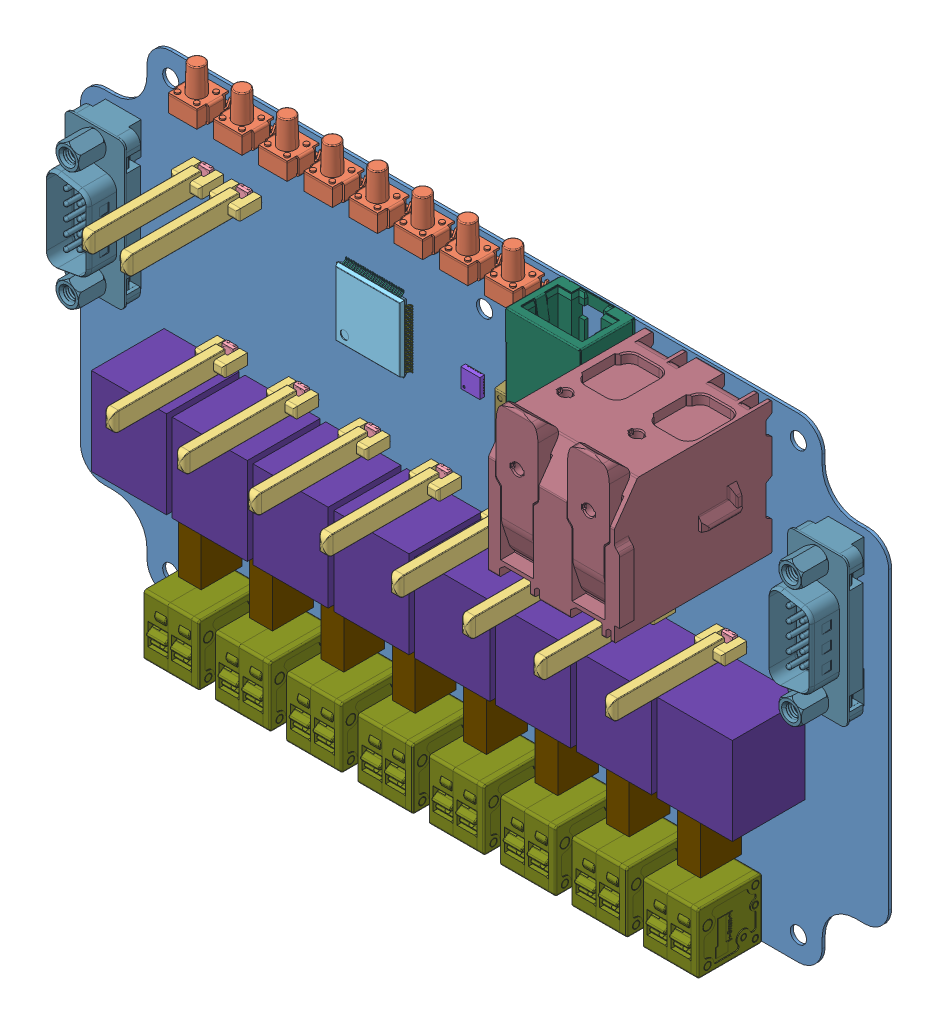
SolidWorks assembly KR-Df-01-EL-00 PCBA 2024_01_12, configuration Default. Lengths in mm.
Overall size (170 105.11 36.71).
192 component instances, 18 part files, 0 mates.
Components (placement in the parent):
- KR-Df-01-EL-00 PCBA 2024_01_12.step-1: KR-Df-01-EL-00 PCBA 2024_01_12.step [Default] at origin size (170 105.11 36.71)
  - Board.step-1: Board.step [Default] at origin size (170 100 0.62)
    - Open CASCADE STEP translator 7.5 2.1.1.step-1: Open CASCADE STEP translator 7.5 2.1.1.step [Default] at (0 0 -0.6237) size (170 100 0.62)
  - S607.step-1: S607.step [Default] at origin size (8.41 12.37 10.52)
    - 1-1825027-1.step-1: 1-1825027-1.step [Default] at (95 95.3 0) x (-1 0 0) z (0 1 0) size (8.41 10.52 12.37)
  - S606.step-1: S606.step [Default] at origin size (8.41 12.37 10.52)
    - 1-1825027-1.step-1: 1-1825027-1.step [Default] at (85.5 95.3 0) x (-1 0 0) z (0 1 0) size (8.41 10.52 12.37)
  - S605.step-1: S605.step [Default] at origin size (8.41 12.37 10.52)
    - 1-1825027-1.step-1: 1-1825027-1.step [Default] at (76 95.3 0) x (-1 0 0) z (0 1 0) size (8.41 10.52 12.37)
  - S604.step-1: S604.step [Default] at origin size (8.41 12.37 10.52)
    - 1-1825027-1.step-1: 1-1825027-1.step [Default] at (66.5 95.3 0) x (-1 0 0) z (0 1 0) size (8.41 10.52 12.37)
  - S603.step-1: S603.step [Default] at origin size (8.41 12.37 10.52)
    - 1-1825027-1.step-1: 1-1825027-1.step [Default] at (57 95.3 0) x (-1 0 0) z (0 1 0) size (8.41 10.52 12.37)
  - S602.step-1: S602.step [Default] at origin size (8.41 12.37 10.52)
    - 1-1825027-1.step-1: 1-1825027-1.step [Default] at (47.5 95.3 0) x (-1 0 0) z (0 1 0) size (8.41 10.52 12.37)
  - S601.step-1: S601.step [Default] at origin size (8.41 12.37 10.52)
    - 1-1825027-1.step-1: 1-1825027-1.step [Default] at (38 95.3 0) x (-1 0 0) z (0 1 0) size (8.41 10.52 12.37)
  - S600.step-1: S600.step [Default] at origin size (8.41 12.37 10.52)
    - 1-1825027-1.step-1: 1-1825027-1.step [Default] at (28.5 95.3 0) x (-1 0 0) z (0 1 0) size (8.41 10.52 12.37)
  - ME609.step-1: ME609.step [Default] at origin size (6.36 3.96 28.65)
    - BIVAR__INC_VLPR-24-1028-2_RGB8421504.step-1: BIVAR__INC_VLPR-24-1028-2_RGB8421504.step [Default] at (27 82 19.1) x (0 1 0) z (1 0 0) size (3.96 28.65 6.35)
  - ME608.step-1: ME608.step [Default] at origin size (6.36 3.96 28.65)
    - BIVAR__INC_VLPR-24-1028-2_RGB8421504.step-1: BIVAR__INC_VLPR-24-1028-2_RGB8421504.step [Default] at (35 82 19.1) x (0 1 0) z (1 0 0) size (3.96 28.65 6.35)
  - ME607.step-1: ME607.step [Default] at origin size (6.36 3.96 28.65)
    - BIVAR__INC_VLPR-24-1028-2_RGB8421504.step-1: BIVAR__INC_VLPR-24-1028-2_RGB8421504.step [Default] at (137 52 19.1) x (0 1 0) z (1 0 0) size (3.96 28.65 6.35)
  - ME606.step-1: ME606.step [Default] at origin size (6.36 3.96 28.65)
    - BIVAR__INC_VLPR-24-1028-2_RGB8421504.step-1: BIVAR__INC_VLPR-24-1028-2_RGB8421504.step [Default] at (122 52 19.1) x (0 1 0) z (1 0 0) size (3.96 28.65 6.35)
  - ME605.step-1: ME605.step [Default] at origin size (6.36 3.96 28.65)
    - BIVAR__INC_VLPR-24-1028-2_RGB8421504.step-1: BIVAR__INC_VLPR-24-1028-2_RGB8421504.step [Default] at (107 52 19.1) x (0 1 0) z (1 0 0) size (3.96 28.65 6.35)
  - ME604.step-1: ME604.step [Default] at origin size (6.36 3.96 28.65)
    - BIVAR__INC_VLPR-24-1028-2_RGB8421504.step-1: BIVAR__INC_VLPR-24-1028-2_RGB8421504.step [Default] at (92 52 19.1) x (0 1 0) z (1 0 0) size (3.96 28.65 6.35)
  - ME603.step-1: ME603.step [Default] at origin size (6.36 3.96 28.65)
    - BIVAR__INC_VLPR-24-1028-2_RGB8421504.step-1: BIVAR__INC_VLPR-24-1028-2_RGB8421504.step [Default] at (77 52 19.1) x (0 1 0) z (1 0 0) size (3.96 28.65 6.35)
  - ME602.step-1: ME602.step [Default] at origin size (6.36 3.96 28.65)
    - BIVAR__INC_VLPR-24-1028-2_RGB8421504.step-1: BIVAR__INC_VLPR-24-1028-2_RGB8421504.step [Default] at (62 52 19.1) x (0 1 0) z (1 0 0) size (3.96 28.65 6.35)
  - ME601.step-1: ME601.step [Default] at origin size (6.36 3.96 28.65)
    - BIVAR__INC_VLPR-24-1028-2_RGB8421504.step-1: BIVAR__INC_VLPR-24-1028-2_RGB8421504.step [Default] at (47 52 19.1) x (0 1 0) z (1 0 0) size (3.96 28.65 6.35)
  - ME600.step-1: ME600.step [Default] at origin size (6.36 3.96 28.65)
    - BIVAR__INC_VLPR-24-1028-2_RGB8421504.step-1: BIVAR__INC_VLPR-24-1028-2_RGB8421504.step [Default] at (32 52 19.1) x (0 1 0) z (1 0 0) size (3.96 28.65 6.35)
  - D609.step-1: D609.step [Default] at origin size (2.4 2.7 1.1)
    - IN-PI22TAT.step-1: IN-PI22TAT.step [Default] at (27 82 0) x (0 1 0) z (1 0 0) size (2.7 1.1 2.4)
  - D608.step-1: D608.step [Default] at origin size (2.4 2.7 1.1)
    - IN-PI22TAT.step-1: IN-PI22TAT.step [Default] at (35 82 0) x (0 1 0) z (1 0 0) size (2.7 1.1 2.4)
  - D607.step-1: D607.step [Default] at origin size (2.4 2.7 1.1)
    - IN-PI22TAT.step-1: IN-PI22TAT.step [Default] at (137 52 0) x (0 -1 0) z (-1 0 0) size (2.7 1.1 2.4)
  - D606.step-1: D606.step [Default] at origin size (2.4 2.7 1.1)
    - IN-PI22TAT.step-1: IN-PI22TAT.step [Default] at (122 52 0) x (0 -1 0) z (-1 0 0) size (2.7 1.1 2.4)
  - D605.step-1: D605.step [Default] at origin size (2.4 2.7 1.1)
    - IN-PI22TAT.step-1: IN-PI22TAT.step [Default] at (107 52 0) x (0 -1 0) z (-1 0 0) size (2.7 1.1 2.4)
  - D604.step-1: D604.step [Default] at origin size (2.4 2.7 1.1)
    - IN-PI22TAT.step-1: IN-PI22TAT.step [Default] at (92 52 0) x (0 -1 0) z (-1 0 0) size (2.7 1.1 2.4)
  - D603.step-1: D603.step [Default] at origin size (2.4 2.7 1.1)
    - IN-PI22TAT.step-1: IN-PI22TAT.step [Default] at (77 52 0) x (0 -1 0) z (-1 0 0) size (2.7 1.1 2.4)
  - D602.step-1: D602.step [Default] at origin size (2.4 2.7 1.1)
    - IN-PI22TAT.step-1: IN-PI22TAT.step [Default] at (62 52 0) x (0 -1 0) z (-1 0 0) size (2.7 1.1 2.4)
  - D601.step-1: D601.step [Default] at origin size (2.4 2.7 1.1)
    - IN-PI22TAT.step-1: IN-PI22TAT.step [Default] at (47 52 0) x (0 -1 0) z (-1 0 0) size (2.7 1.1 2.4)
  - D600.step-1: D600.step [Default] at origin size (2.4 2.7 1.1)
    - IN-PI22TAT.step-1: IN-PI22TAT.step [Default] at (32 52 0) x (0 -1 0) z (-1 0 0) size (2.7 1.1 2.4)
  - U500.step-1: U500.step [Default] at origin size (16 16 1.6)
    - STM32H573VIT6_RGB8421504.step-1: STM32H573VIT6_RGB8421504.step [Default] at (62 73 0) x (0 1 0) z (0 0 1) size (16 16 1.6)
      - Body.step-1: Body.step [Default] at origin size (14 14 1.5)
      - PinsArrayLR.step-1: PinsArrayLR.step [Default] at origin size (16 12.22 0.86)
      - PinsArrayTB.step-1: PinsArrayTB.step [Default] at origin size (12.22 16 0.86)
  - U200.step-1: U200.step [Default] at origin size (4 4 1)
    - 6102634304.step-1: 6102634304.step [Default] at (83 72 0) x (0 1 0) z (0 0 1) size (4 4 1)
      - Body-0.step-1: Body-0.step [Default] at (-2 -2 0) size (4 4 1)
        - Open CASCADE STEP translator 6.8 14.2.1.step-1: Open CASCADE STEP translator 6.8 14.2.1.step [Default] at origin size (4 4 1)
      - Pin_Shape.step-1: Pin_Shape.step [Default] at (-2 -1.37 0) size (0.4 0.24 0.2)
        - Open CASCADE STEP translator 6.8 14.4.1.step-1: Open CASCADE STEP translator 6.8 14.4.1.step [Default] at origin size (0.4 0.24 0.2)
      - Pin_Shape.step-2: Pin_Shape.step [Default] at (2 1.37 0) x (-1 0 0) z (0 0 1) size (0.4 0.24 0.2)
        - Open CASCADE STEP translator 6.8 14.4.1.step-1: Open CASCADE STEP translator 6.8 14.4.1.step [Default] at origin size (0.4 0.24 0.2)
      - Pin_Shape.step-3: Pin_Shape.step [Default] at (-2 -0.87 0) size (0.4 0.24 0.2)
        - Open CASCADE STEP translator 6.8 14.4.1.step-1: Open CASCADE STEP translator 6.8 14.4.1.step [Default] at origin size (0.4 0.24 0.2)
      - Pin_Shape.step-4: Pin_Shape.step [Default] at (2 0.87 0) x (-1 0 0) z (0 0 1) size (0.4 0.24 0.2)
        - Open CASCADE STEP translator 6.8 14.4.1.step-1: Open CASCADE STEP translator 6.8 14.4.1.step [Default] at origin size (0.4 0.24 0.2)
      - Pin_Shape.step-5: Pin_Shape.step [Default] at (-2 -0.37 0) size (0.4 0.24 0.2)
        - Open CASCADE STEP translator 6.8 14.4.1.step-1: Open CASCADE STEP translator 6.8 14.4.1.step [Default] at origin size (0.4 0.24 0.2)
      - Pin_Shape.step-6: Pin_Shape.step [Default] at (2 0.37 0) x (-1 0 0) z (0 0 1) size (0.4 0.24 0.2)
        - Open CASCADE STEP translator 6.8 14.4.1.step-1: Open CASCADE STEP translator 6.8 14.4.1.step [Default] at origin size (0.4 0.24 0.2)
      - Pin_Shape.step-7: Pin_Shape.step [Default] at (-2 0.13 0) size (0.4 0.24 0.2)
        - Open CASCADE STEP translator 6.8 14.4.1.step-1: Open CASCADE STEP translator 6.8 14.4.1.step [Default] at origin size (0.4 0.24 0.2)
      - Pin_Shape.step-8: Pin_Shape.step [Default] at (2 -0.13 0) x (-1 0 0) z (0 0 1) size (0.4 0.24 0.2)
        - Open CASCADE STEP translator 6.8 14.4.1.step-1: Open CASCADE STEP translator 6.8 14.4.1.step [Default] at origin size (0.4 0.24 0.2)
      - Pin_Shape.step-9: Pin_Shape.step [Default] at (-2 0.63 0) size (0.4 0.24 0.2)
        - Open CASCADE STEP translator 6.8 14.4.1.step-1: Open CASCADE STEP translator 6.8 14.4.1.step [Default] at origin size (0.4 0.24 0.2)
      - Pin_Shape.step-10: Pin_Shape.step [Default] at (2 -0.63 0) x (-1 0 0) z (0 0 1) size (0.4 0.24 0.2)
        - Open CASCADE STEP translator 6.8 14.4.1.step-1: Open CASCADE STEP translator 6.8 14.4.1.step [Default] at origin size (0.4 0.24 0.2)
      - Pin_Shape.step-11: Pin_Shape.step [Default] at (-2 1.13 0) size (0.4 0.24 0.2)
        - Open CASCADE STEP translator 6.8 14.4.1.step-1: Open CASCADE STEP translator 6.8 14.4.1.step [Default] at origin size (0.4 0.24 0.2)
      - Pin_Shape.step-12: Pin_Shape.step [Default] at (2 -1.13 0) x (-1 0 0) z (0 0 1) size (0.4 0.24 0.2)
        - Open CASCADE STEP translator 6.8 14.4.1.step-1: Open CASCADE STEP translator 6.8 14.4.1.step [Default] at origin size (0.4 0.24 0.2)
      - Pin_Shape.step-13: Pin_Shape.step [Default] at (-1.13 -2 0) x (0 1 0) z (0 0 1) size (0.4 0.24 0.2)
        - Open CASCADE STEP translator 6.8 14.4.1.step-1: Open CASCADE STEP translator 6.8 14.4.1.step [Default] at origin size (0.4 0.24 0.2)
      - Pin_Shape.step-14: Pin_Shape.step [Default] at (1.13 2 0) x (0 -1 0) z (0 0 1) size (0.4 0.24 0.2)
        - Open CASCADE STEP translator 6.8 14.4.1.step-1: Open CASCADE STEP translator 6.8 14.4.1.step [Default] at origin size (0.4 0.24 0.2)
      - Pin_Shape.step-15: Pin_Shape.step [Default] at (-0.63 -2 0) x (0 1 0) z (0 0 1) size (0.4 0.24 0.2)
        - Open CASCADE STEP translator 6.8 14.4.1.step-1: Open CASCADE STEP translator 6.8 14.4.1.step [Default] at origin size (0.4 0.24 0.2)
      - Pin_Shape.step-16: Pin_Shape.step [Default] at (0.63 2 0) x (0 -1 0) z (0 0 1) size (0.4 0.24 0.2)
        - Open CASCADE STEP translator 6.8 14.4.1.step-1: Open CASCADE STEP translator 6.8 14.4.1.step [Default] at origin size (0.4 0.24 0.2)
      - Pin_Shape.step-17: Pin_Shape.step [Default] at (-0.13 -2 0) x (0 1 0) z (0 0 1) size (0.4 0.24 0.2)
        - Open CASCADE STEP translator 6.8 14.4.1.step-1: Open CASCADE STEP translator 6.8 14.4.1.step [Default] at origin size (0.4 0.24 0.2)
      - Pin_Shape.step-18: Pin_Shape.step [Default] at (0.13 2 0) x (0 -1 0) z (0 0 1) size (0.4 0.24 0.2)
        - Open CASCADE STEP translator 6.8 14.4.1.step-1: Open CASCADE STEP translator 6.8 14.4.1.step [Default] at origin size (0.4 0.24 0.2)
      - Pin_Shape.step-19: Pin_Shape.step [Default] at (0.37 -2 0) x (0 1 0) z (0 0 1) size (0.4 0.24 0.2)
        - Open CASCADE STEP translator 6.8 14.4.1.step-1: Open CASCADE STEP translator 6.8 14.4.1.step [Default] at origin size (0.4 0.24 0.2)
      - Pin_Shape.step-20: Pin_Shape.step [Default] at (-0.37 2 0) x (0 -1 0) z (0 0 1) size (0.4 0.24 0.2)
        - Open CASCADE STEP translator 6.8 14.4.1.step-1: Open CASCADE STEP translator 6.8 14.4.1.step [Default] at origin size (0.4 0.24 0.2)
      - Pin_Shape.step-21: Pin_Shape.step [Default] at (0.87 -2 0) x (0 1 0) z (0 0 1) size (0.4 0.24 0.2)
        - Open CASCADE STEP translator 6.8 14.4.1.step-1: Open CASCADE STEP translator 6.8 14.4.1.step [Default] at origin size (0.4 0.24 0.2)
      - Pin_Shape.step-22: Pin_Shape.step [Default] at (-0.87 2 0) x (0 -1 0) z (0 0 1) size (0.4 0.24 0.2)
        - Open CASCADE STEP translator 6.8 14.4.1.step-1: Open CASCADE STEP translator 6.8 14.4.1.step [Default] at origin size (0.4 0.24 0.2)
      - Pin_Shape.step-23: Pin_Shape.step [Default] at (1.37 -2 0) x (0 1 0) z (0 0 1) size (0.4 0.24 0.2)
        - Open CASCADE STEP translator 6.8 14.4.1.step-1: Open CASCADE STEP translator 6.8 14.4.1.step [Default] at origin size (0.4 0.24 0.2)
      - Pin_Shape.step-24: Pin_Shape.step [Default] at (-1.37 2 0) x (0 -1 0) z (0 0 1) size (0.4 0.24 0.2)
        - Open CASCADE STEP translator 6.8 14.4.1.step-1: Open CASCADE STEP translator 6.8 14.4.1.step [Default] at origin size (0.4 0.24 0.2)
      - Open CASCADE STEP translator 6.8 14.1.step-1: Open CASCADE STEP translator 6.8 14.1.step [Default] at (-2 -2 0) size (0.51 0.51 0.01)
      - Thermal_Shape.step-1: Thermal_Shape.step [Default] at (-1.25 -1.25 -0.001) size (2.5 2.5 0)
  - T200.step-1: T200.step [Default] at origin size (9.3 12.8 5.68)
    - PT61018PEL.step-1: PT61018PEL.step [Default] at (99.35 78.3999 5.65) x (0 -1 0) z (1 0 0) size (12.8 5.68 9.3)
  - J400.step-1: J400.step [Default] at origin size (27.81 32.01 33.2)
    - 2616-1352.step-1: 2616-1352.step [Default] at (120.5 89.5 0) x (0 1 0) z (1 0 0) size (32.01 33.2 27.81)
  - J301.step-1: J301.step [Default] at origin size (12.55 30.81 15.4)
    - L717TSEH09POL2RM8--3DModel-STEP-533217.step-1: L717TSEH09POL2RM8--3DModel-STEP-533217.step [Default] at (167.275 53.58 0) x (0 1 0) z (1 0 0) size (30.81 15.4 12.55)
  - J300.step-1: J300.step [Default] at origin size (12.55 30.81 15.4)
    - L717TSEH09POL2RM8--3DModel-STEP-533217.step-1: L717TSEH09POL2RM8--3DModel-STEP-533217.step [Default] at (15.275 53.58 0) x (0 1 0) z (1 0 0) size (30.81 15.4 12.55)
  - P200.step-1: P200.step [Default] at origin size (16.33 18.55 13.95)
    - M-RJLSE-4X381-01T-REVT1.step-1: M-RJLSE-4X381-01T-REVT1.step [Default] at (108.9999 100.025 0) x (1 0 0) z (0 1 0) size (16.33 13.95 18.55)
  - P103.step-1: P103.step [Default] at origin size (11.62 12.71 17.41)
    - DGPS2.5R-5.0-02P-14-00Z(H).step-1: DGPS2.5R-5.0-02P-14-00Z(H).step [Default] at (76.8 -0.2 0) x (1 0 0) z (0 -1 0) size (11.62 17.41 12.71)
  - P101.step-1: P101.step [Default] at origin size (11.62 12.71 17.41)
    - DGPS2.5R-5.0-02P-14-00Z(H).step-1: DGPS2.5R-5.0-02P-14-00Z(H).step [Default] at (46.8 -0.2 0) x (1 0 0) z (0 -1 0) size (11.62 17.41 12.71)
  - P106.step-1: P106.step [Default] at origin size (11.62 12.71 17.41)
    - DGPS2.5R-5.0-02P-14-00Z(H).step-1: DGPS2.5R-5.0-02P-14-00Z(H).step [Default] at (121.8 -0.2 0) x (1 0 0) z (0 -1 0) size (11.62 17.41 12.71)
  - P104.step-1: P104.step [Default] at origin size (11.62 12.71 17.41)
    - DGPS2.5R-5.0-02P-14-00Z(H).step-1: DGPS2.5R-5.0-02P-14-00Z(H).step [Default] at (91.8 -0.2 0) x (1 0 0) z (0 -1 0) size (11.62 17.41 12.71)
  - P100.step-1: P100.step [Default] at origin size (11.62 12.71 17.41)
    - DGPS2.5R-5.0-02P-14-00Z(H).step-1: DGPS2.5R-5.0-02P-14-00Z(H).step [Default] at (31.8 -0.2 0) x (1 0 0) z (0 -1 0) size (11.62 17.41 12.71)
  - P107.step-1: P107.step [Default] at origin size (11.62 12.71 17.41)
    - DGPS2.5R-5.0-02P-14-00Z(H).step-1: DGPS2.5R-5.0-02P-14-00Z(H).step [Default] at (136.8 -0.2 0) x (1 0 0) z (0 -1 0) size (11.62 17.41 12.71)
  - P105.step-1: P105.step [Default] at origin size (11.62 12.71 17.41)
    - DGPS2.5R-5.0-02P-14-00Z(H).step-1: DGPS2.5R-5.0-02P-14-00Z(H).step [Default] at (106.8 -0.2 0) x (1 0 0) z (0 -1 0) size (11.62 17.41 12.71)
  - P102.step-1: P102.step [Default] at origin size (11.62 12.71 17.41)
    - DGPS2.5R-5.0-02P-14-00Z(H).step-1: DGPS2.5R-5.0-02P-14-00Z(H).step [Default] at (61.8 -0.2 0) x (1 0 0) z (0 -1 0) size (11.62 17.41 12.71)
  - K104.step-1: K104.step [Default] at origin size (15.8 18.4 15.29)
    - 6227875488.step-1: 6227875488.step [Default] at (93.5 39.55 0) size (15.8 18.4 15.29)
      - Extruded.step-1: Extruded.step [Default] at origin size (15.8 18.4 15.29)
  - K101.step-1: K101.step [Default] at origin size (15.8 18.4 15.29)
    - 6227875488.step-1: 6227875488.step [Default] at (42.5 39.55 0) size (15.8 18.4 15.29)
      - Extruded.step-1: Extruded.step [Default] at origin size (15.8 18.4 15.29)
  - K106.step-1: K106.step [Default] at origin size (15.8 18.4 15.29)
    - 6227875488.step-1: 6227875488.step [Default] at (127.5 39.55 0) size (15.8 18.4 15.29)
      - Extruded.step-1: Extruded.step [Default] at origin size (15.8 18.4 15.29)
  - K103.step-1: K103.step [Default] at origin size (15.8 18.4 15.29)
    - 6227875488.step-1: 6227875488.step [Default] at (76.5 39.55 0) size (15.8 18.4 15.29)
      - Extruded.step-1: Extruded.step [Default] at origin size (15.8 18.4 15.29)
  - K100.step-1: K100.step [Default] at origin size (15.8 18.4 15.29)
    - 6227875488.step-1: 6227875488.step [Default] at (25.5 39.55 0) size (15.8 18.4 15.29)
      - Extruded.step-1: Extruded.step [Default] at origin size (15.8 18.4 15.29)
  - K107.step-1: K107.step [Default] at origin size (15.8 18.4 15.29)
    - 6227875488.step-1: 6227875488.step [Default] at (144.5 39.55 0) size (15.8 18.4 15.29)
      - Extruded.step-1: Extruded.step [Default] at origin size (15.8 18.4 15.29)
  - K105.step-1: K105.step [Default] at origin size (15.8 18.4 15.29)
    - 6227875488.step-1: 6227875488.step [Default] at (110.5 39.55 0) size (15.8 18.4 15.29)
      - Extruded.step-1: Extruded.step [Default] at origin size (15.8 18.4 15.29)
  - K102.step-1: K102.step [Default] at origin size (15.8 18.4 15.29)
    - 6227875488.step-1: 6227875488.step [Default] at (59.5 39.55 0) size (15.8 18.4 15.29)
      - Extruded.step-1: Extruded.step [Default] at origin size (15.8 18.4 15.29)
  - F103.step-1: F103.step [Default] at origin size (4.8 14.7 8.6)
    - 6227873168.step-1: 6227873168.step [Default] at (76.6 21 0) size (4.8 14.7 8.6)
      - Extruded-1.step-1: Extruded-1.step [Default] at origin size (4.8 14.7 8.6)
  - F101.step-1: F101.step [Default] at origin size (4.8 14.7 8.6)
    - 6227873168.step-1: 6227873168.step [Default] at (46.6 21 0) size (4.8 14.7 8.6)
      - Extruded-1.step-1: Extruded-1.step [Default] at origin size (4.8 14.7 8.6)
  - F106.step-1: F106.step [Default] at origin size (4.8 14.7 8.6)
    - 6227873168.step-1: 6227873168.step [Default] at (121.6 21 0) size (4.8 14.7 8.6)
      - Extruded-1.step-1: Extruded-1.step [Default] at origin size (4.8 14.7 8.6)
  - F104.step-1: F104.step [Default] at origin size (4.8 14.7 8.6)
    - 6227873168.step-1: 6227873168.step [Default] at (91.6 21 0) size (4.8 14.7 8.6)
      - Extruded-1.step-1: Extruded-1.step [Default] at origin size (4.8 14.7 8.6)
  - F100.step-1: F100.step [Default] at origin size (4.8 14.7 8.6)
    - 6227873168.step-1: 6227873168.step [Default] at (31.6 21 0) size (4.8 14.7 8.6)
      - Extruded-1.step-1: Extruded-1.step [Default] at origin size (4.8 14.7 8.6)
  - F107.step-1: F107.step [Default] at origin size (4.8 14.7 8.6)
    - 6227873168.step-1: 6227873168.step [Default] at (136.6 21 0) size (4.8 14.7 8.6)
      - Extruded-1.step-1: Extruded-1.step [Default] at origin size (4.8 14.7 8.6)
  - F105.step-1: F105.step [Default] at origin size (4.8 14.7 8.6)
    - 6227873168.step-1: 6227873168.step [Default] at (106.6 21 0) size (4.8 14.7 8.6)
      - Extruded-1.step-1: Extruded-1.step [Default] at origin size (4.8 14.7 8.6)
  - F102.step-1: F102.step [Default] at origin size (4.8 14.7 8.6)
    - 6227873168.step-1: 6227873168.step [Default] at (61.6 21 0) size (4.8 14.7 8.6)
      - Extruded-1.step-1: Extruded-1.step [Default] at origin size (4.8 14.7 8.6)
